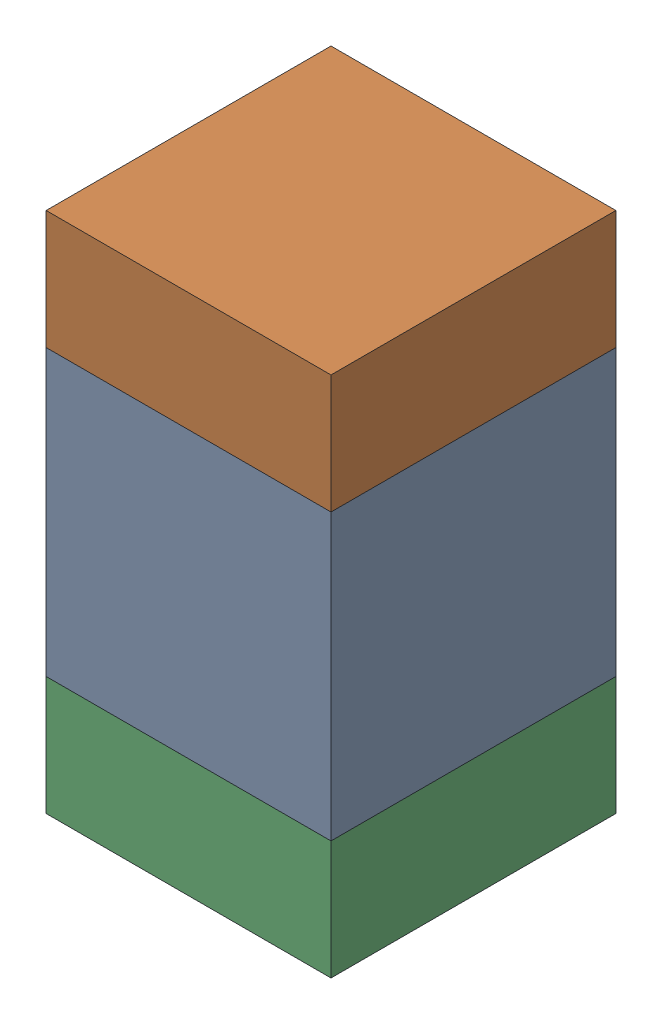
SolidWorks assembly C304_1PCB, configuration Default. Lengths in mm.
Overall size (0.6 1.1 0.6).
6 component instances, 2 part files, 0 mates.
Components (placement in the parent):
- 761606048-1: 761606048 [Default] at (138.45 120.1343 0) size (0.6 0.6 0.6)
  - Extruded_9-1: Extruded_9 [Default] at origin size (0.6 0.6 0.6)
- 854785296-1: 854785296 [Default] at (138.45 120.5593 0) size (0.6 0.25 0.6)
  - Extruded_10-1: Extruded_10 [Default] at origin size (0.6 0.25 0.6)
- 854785296-2: 854785296 [Default] at (138.45 119.7093 0) size (0.6 0.25 0.6)
  - Extruded_10-1: Extruded_10 [Default] at origin size (0.6 0.25 0.6)
